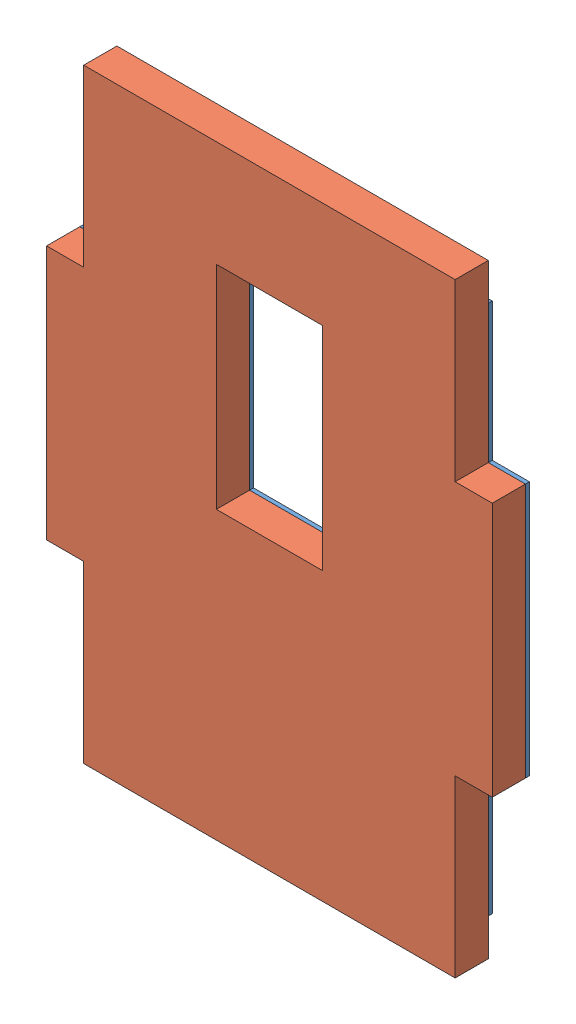
SolidWorks assembly Long Wall, configuration Default. Lengths in mm.
Overall size (336 456 28).
2 component instances, 2 part files, 3 mates.
Components (placement in the parent):
- Long wall acrylic-1: Long wall acrylic [Default] at (-119.0139 -10.8946 25.0764) size (336 400 3)
- Long wall poly-1: Long wall poly [Default] at (-119.0139 -38.8946 28.0764) size (336 456 25)
Mates (geometry in assembly coordinates):
- Coincident1: coincident: plane of Long wall acrylic-1 through (-119.0139 -10.8946 28.0764) normal (0 0 1); plane of Long wall poly-1 through (-119.0139 -38.8946 28.0764) normal (0 0 -1)
- Coincident2: coincident: plane of Long wall acrylic-1 through (79.2068 177.2227 50.0764) normal (1 0 0); plane of Long wall poly-1 through (79.2068 205.2227 53.0764) normal (1 0 0)
- Coincident3: coincident: plane of Long wall acrylic-1 through (107.2068 73.2227 50.0764) normal (0 1 0); plane of Long wall poly-1 through (107.2068 73.2227 53.0764) normal (0 1 0)
